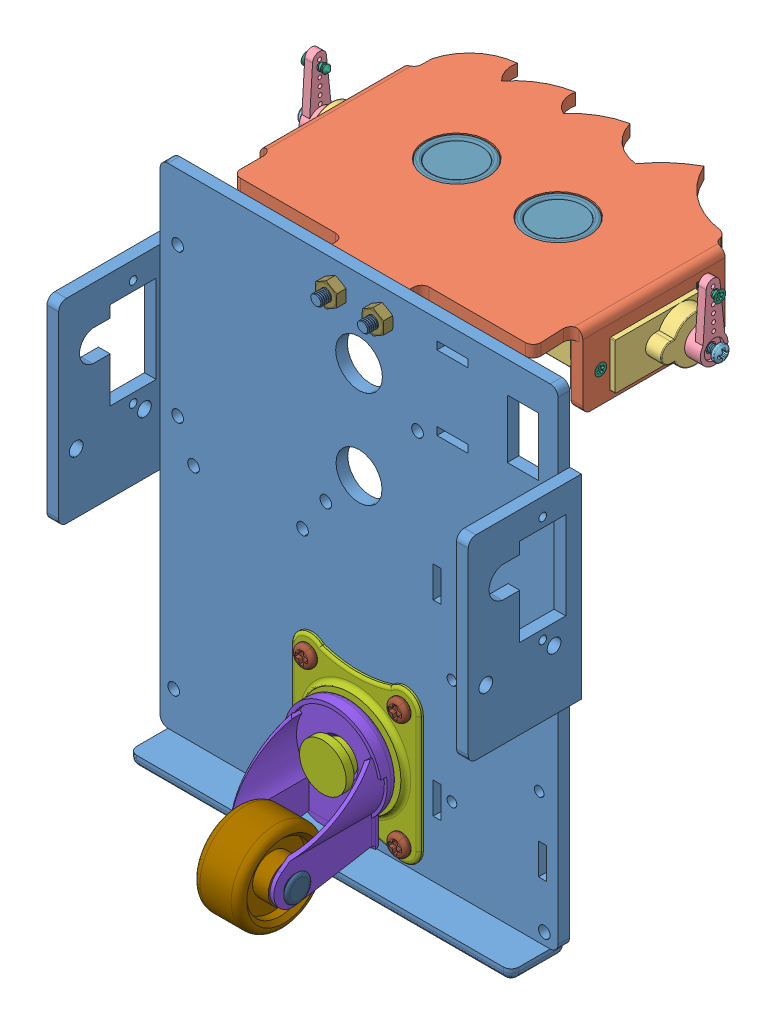
SolidWorks assembly DYOR_3D_AR, configuration Predeterminado. Lengths in mm.
Overall size (108.06 136.43 105.65).
49 component instances, 19 part files, 21 mates.
Components (placement in the parent):
- Base-1: Base [Predeterminado] at (60.418 -80.9125 12.5389) size (108 128.45 29)
- Front_AR-1: Front_AR [Predeterminado] at (-130.0773 39.5388 -125.3997) x (1 0 0) z (0 1 0) size (82.74 65.06 18.8)
- AR1-1: AR1 [Predeterminado] at (-137.3672 230.6023 -131.927) size (34.06 21.84 31.9)
  - sg90-2: sg90 [Default] at (126.818 -193.0635 98.9775) x (0 0 1) z (0 -1 0) size (31.9 29.9 11.8)
  - SG90 plastic Horn-2: SG90 plastic Horn [Default] at (97.368 -198.9635 104.8775) x (0 0.999767 0.021606) z (0 -0.021606 0.999767) size (19.4 4 7.07)
  - (M2_3_mm)_90116A007_METRIC 316 SS PAN HEAD PHILLIPS MACHINE SCREW-2: (M2_3_mm)_90116A007_METRIC 316 SS PAN HEAD PHILLIPS MACHINE SCREW [90116A007] at (97.368 -198.9635 104.8775) x (0 0 1) z (-1 0 0) size (4 4 4.68)
  - M2x6 SelfTap Screw-1: M2x6 SelfTap Screw [Predeterminado] at (93.868 -186.4635 104.8775) x (0 0.924225 0.381849) z (-1 0 0) size (3.4 3.28 6)
  - M2x6 SelfTap Screw-3: M2x6 SelfTap Screw [Predeterminado] at (105.418 -198.9635 123.8775) x (0 0.924225 0.381849) z (-1 0 0) size (3.4 3.28 6)
  - M2x6 SelfTap Screw-5: M2x6 SelfTap Screw [Predeterminado] at (105.418 -198.9635 96.5775) x (0 0.924225 0.381849) z (-1 0 0) size (3.4 3.28 6)
- AR2-1: AR2 [Predeterminado] at (-145.9856 230.6023 -131.927) size (34.06 21.82 31.9)
  - sg90-1: sg90 [Default] at (175.3764 -204.8635 98.9775) x (0 0 1) z (0 1 0) size (31.9 29.9 11.8)
  - SG90 plastic Horn-1: SG90 plastic Horn [Default] at (204.8264 -198.9635 104.8775) x (0 0.999858 0.016879) z (0 0.016879 -0.999858) size (19.4 4 7.07)
  - (M2_3_mm)_90116A007_METRIC 316 SS PAN HEAD PHILLIPS MACHINE SCREW-1: (M2_3_mm)_90116A007_METRIC 316 SS PAN HEAD PHILLIPS MACHINE SCREW [90116A007] at (204.8264 -198.9635 104.8775) x (0 0 -1) z (1 0 0) size (4 4 4.68)
  - M2x6 SelfTap Screw-2: M2x6 SelfTap Screw [Predeterminado] at (208.3264 -186.4635 104.8775) x (0 -0.924225 -0.381849) z (1 0 0) size (3.4 3.28 6)
  - M2x6 SelfTap Screw-4: M2x6 SelfTap Screw [Predeterminado] at (196.7764 -198.9635 123.8775) x (0 -0.924225 -0.381849) z (1 0 0) size (3.4 3.28 6)
  - M2x6 SelfTap Screw-6: M2x6 SelfTap Screw [Predeterminado] at (196.7764 -198.9635 96.5775) x (0 -0.924225 -0.381849) z (1 0 0) size (3.4 3.28 6)
- CA-1: CA [Predeterminado] at (-2.207 18.0036 0) size (33 45.94 43.2)
  - Caster Wheel-1: Caster Wheel [Default] at (57.6387 -78.841 57.7572) x (0 1 0) z (-1 0 0) size (45.94 37.59 33)
    - caster holder-1: caster holder [Default] at (-24.0751 44.7184 29.5137) x (1 0 0) z (0 0 -1) size (39 9.27 33)
    - holder-1: holder [Default] at (-1.5751 42.9484 46.0137) x (0 0 1) z (1 0 0) size (25 28.07 31.31)
    - caster wheel-1: caster wheel [Default] at (-15.6961 19.9484 46.0137) x (0.997275 0.073773 0) z (0 0 1) size (23 23 14)
    - Part4-1: Part4 [Default] at (-15.6961 19.9484 55.0137) x (-0.978448 0.206495 0) z (0 0 -1) size (7 7 20)
  - M3x6 Philips Screw-1: M3x6 Philips Screw [Predeterminado] at (23.625 -65.4161 13.5389) size (5.3 5.3 7.81)
  - M3x6 Philips Screw-2: M3x6 Philips Screw [Predeterminado] at (-0.375 -65.4161 13.5389) size (5.3 5.3 7.81)
  - M3x6 Philips Screw-3: M3x6 Philips Screw [Predeterminado] at (-0.375 -95.4161 13.5389) size (5.3 5.3 7.81)
  - M3x6 Philips Screw-4: M3x6 Philips Screw [Predeterminado] at (23.625 -95.4161 13.5389) size (5.3 5.3 7.81)
  - M3 Nut-1: M3 Nut [Predeterminado] at (23.625 -65.4161 11.0389) size (6.27 6.27 2.71)
  - M3 Nut-2: M3 Nut [Predeterminado] at (-0.375 -65.4161 11.0389) size (6.27 6.27 2.71)
  - M3 Nut-3: M3 Nut [Predeterminado] at (-0.375 -95.4161 11.0389) size (6.27 6.27 2.71)
  - M3 Nut-4: M3 Nut [Predeterminado] at (23.625 -95.4161 11.0389) size (6.27 6.27 2.71)
- HC-SR04 Ping Sensor-1: HC-SR04 Ping Sensor [Default] at (9.418 28.7888 -25.5054) x (0 0 -1) z (0 1 0) size (25.18 45 18.07)
  - PCB-1: PCB [Default] at origin size (20.5 45 1.75)
  - Transducer-1: Transducer [Default] at (0 -13 13.25) x (1 0 0) z (0 -1 0) size (15.88 12 15.88)
  - Transducer-2: Transducer [Default] at (0 13 13.25) x (1 0 0) z (0 -1 0) size (15.88 12 15.88)
  - 3 Pin Header 90 Degree-1: 3 Pin Header 90 Degree [Default] at (8.4275 0 -1.25) x (-1 0 0) z (0 -1 0) size (8 7.82 10)
  - 14 Pin SMT-1: 14 Pin SMT [Default] at (-0.35 -18.5 -0.85) x (0 -1 0) z (1 0 0) size (6 1.6 8.8)
  - 14 Pin SMT-2: 14 Pin SMT [Default] at (0 -0.3826 -0.85) x (1 0 0) z (0 1 0) size (6 1.6 8.8)
  - 14 Pin SMT-3: 14 Pin SMT [Default] at (0 17.5274 -0.85) x (1 0 0) z (0 1 0) size (6 1.6 8.8)
  - Cap1 SMT-1: Cap1 SMT [Default] at (-1.755 7.4774 -0.9689) x (0 1 0) z (-1 0 0) size (4.5 1.84 1.75)
  - Cap1 SMT-2: Cap1 SMT [Default] at (6.835 7.4774 -0.9689) x (0 1 0) z (-1 0 0) size (4.5 1.84 1.75)
  - Cap1 SMT-3: Cap1 SMT [Default] at (-6.835 7.4774 -0.9689) x (0 1 0) z (-1 0 0) size (4.5 1.84 1.75)
  - Cap1 SMT-4: Cap1 SMT [Default] at (4.295 7.4774 -0.9689) x (0 1 0) z (-1 0 0) size (4.5 1.84 1.75)
  - Cap1 SMT-5: Cap1 SMT [Default] at (1.755 7.4774 -0.9689) x (0 1 0) z (-1 0 0) size (4.5 1.84 1.75)
  - Cap1 SMT-6: Cap1 SMT [Default] at (-4.295 7.4774 -0.9689) x (0 1 0) z (-1 0 0) size (4.5 1.84 1.75)
  - HC-SR04 Crystal-1: HC-SR04 Crystal [Default] at (-8.3 0 1.75) x (0 -1 0) z (0 0 1) size (10 3.5 2.7)
- M3x10 Philips Screw-1: M3x10 Philips Screw [Predeterminado] at (3.418 36.0388 7.5389) x (-0.459458 -0.8882 0) z (0 0 -1) size (5.3 5.3 11.8)
- M3x10 Philips Screw-2: M3x10 Philips Screw [Predeterminado] at (15.418 36.0388 7.5389) x (-0.386504 -0.922288 0) z (0 0 -1) size (5.3 5.3 11.8)
- M3 Nut-1: M3 Nut [Predeterminado] at (15.418 36.0388 16.5389) size (6.27 6.27 2.71)
- M3 Nut-2: M3 Nut [Predeterminado] at (3.418 36.0388 16.5389) size (6.27 6.27 2.71)
Mates (geometry in assembly coordinates):
- Coincidente16: coincident: plane of Base-1 through (-39.582 40.5388 9.5389) normal (0 0 -1); plane of Front_AR-1 through (-0.582 42.5388 9.5389) normal (0 0 1)
- Coincidente17: coincident: plane of Front_AR-1 through (-28.9492 23.7388 -39.9495) normal (1 0 0); plane of AR1-1/sg90-2 through (-28.9492 37.5388 -37.6495) normal (-1 0 0)
- Coincidente18: coincident: plane of Front_AR-1 through (-16.1492 37.5388 -10.4495) normal (0 -1 0); plane of AR1-1/sg90-2 through (-10.5492 37.5388 -32.9495) normal (0 1 0)
- Coincidente19: coincident: plane of Front_AR-1 through (-16.1492 37.5388 -32.9495) normal (0 0 1); plane of AR1-1/sg90-2 through (-10.5492 25.7388 -32.9495) normal (0 0 -1)
- Coincidente20: coincident: plane of Front_AR-1 through (47.7908 23.7388 -39.9495) normal (-1 0 0); plane of AR2-1/sg90-1 through (47.7908 25.7388 -37.6495) normal (1 0 0)
- Coincidente21: coincident: plane of Front_AR-1 through (34.9908 25.7388 -32.9495) normal (0 1 0); plane of AR2-1/sg90-1 through (29.3908 25.7388 -32.9495) normal (0 -1 0)
- Coincidente22: coincident: plane of Front_AR-1 through (34.9908 25.7388 -10.4495) normal (0 0 -1); plane of AR2-1/sg90-1 through (29.3908 37.5388 -10.4495) normal (0 0 1)
- Coincidente23: coincident: plane of Base-1 through (-39.582 40.5388 12.5389) normal (0 0 1); plane of CA-1/Caster Wheel-1/caster holder-1 through (9.418 -17.6143 12.5389) normal (0 0 -1)
- Concéntrica1: concentric: circle of Base-1; circle of CA-1/Caster Wheel-1/caster holder-1
- Concéntrica2: concentric: circle of Base-1; circle of CA-1/Caster Wheel-1/caster holder-1
- Concéntrica3: concentric: circle of Front_AR-1; circle of HC-SR04 Ping Sensor-1/Transducer-2
- Concéntrica4: concentric: circle of Front_AR-1; circle of HC-SR04 Ping Sensor-1/Transducer-1
- Coincidente24: coincident: plane of Front_AR-1 through (-30.9492 42.5388 -1.4495) normal (0 1 0); plane of HC-SR04 Ping Sensor-1/Transducer-1 through (22.418 42.5388 -33.4454) normal (0 1 0)
- Coincidente25: coincident: plane of Front_AR-1 through (3.418 36.0388 7.5389) normal (0 0 -1); plane of M3x10 Philips Screw-1 through (1.9969 36.7739 7.5389) normal (0 0 1)
- Concéntrica5: concentric: circle of Front_AR-1; circle of M3x10 Philips Screw-1
- Coincidente26: coincident: plane of Front_AR-1 through (15.418 36.0388 7.5389) normal (0 0 -1); plane of M3x10 Philips Screw-2 through (13.9424 36.6572 7.5389) normal (0 0 1)
- Concéntrica6: concentric: circle of Front_AR-1; circle of M3x10 Philips Screw-2
- Coincidente30: coincident: plane of Base-1 through (-39.582 40.5388 12.5389) normal (0 0 1); plane of M3 Nut-1 through (15.418 36.0388 12.5389) normal (0 0 -1)
- Coincidente31: coincident: plane of Base-1 through (-39.582 40.5388 12.5389) normal (0 0 1); plane of M3 Nut-2 through (3.418 36.0388 12.5389) normal (0 0 -1)
- Concéntrica7: concentric: circle of Base-1; circle of M3 Nut-1
- Concéntrica8: concentric: circle of Base-1; circle of M3 Nut-2
